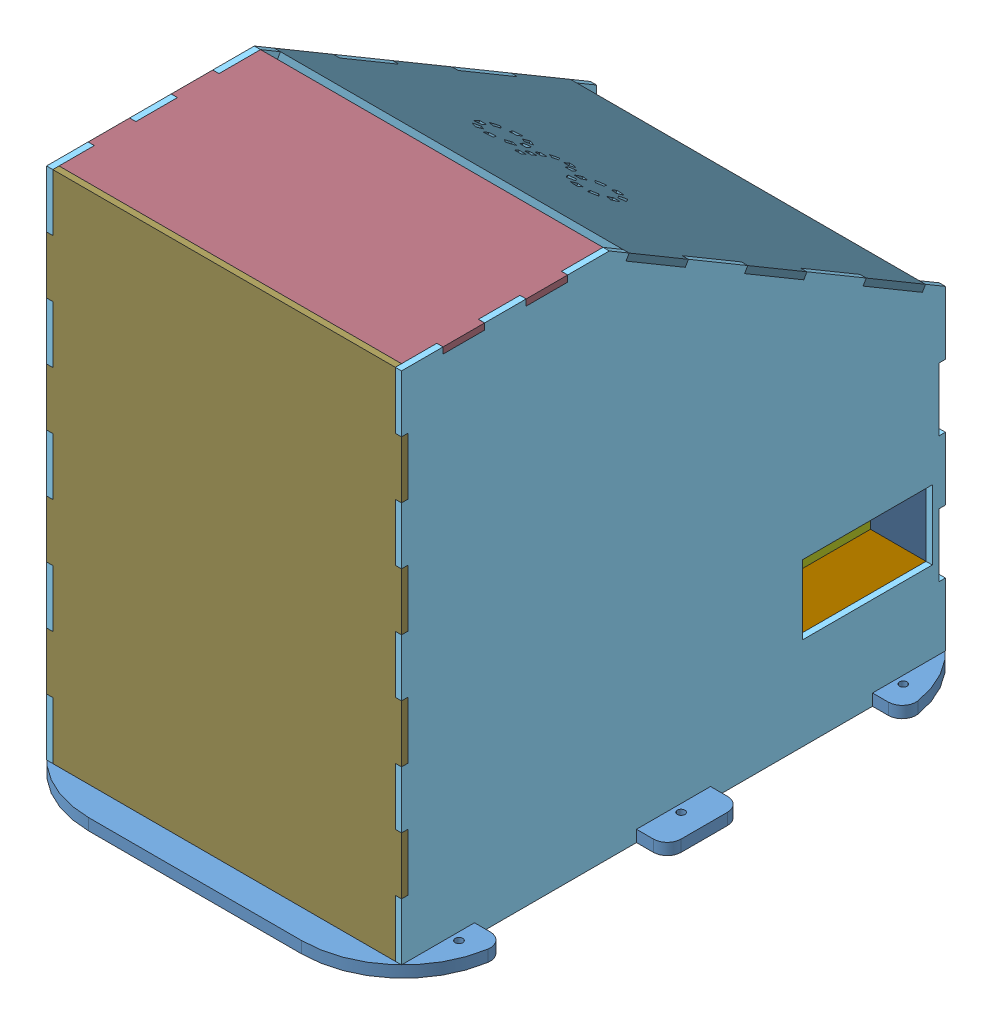
SolidWorks assembly Assem1_2, configuration Varsayılan. Lengths in mm.
Overall size (180 227.3 260).
24 component instances, 14 part files, 26 mates.
Components (placement in the parent):
- mainboard_last-1: mainboard_last [Varsayılan] at (-3.7025 2.4058 260) size (180 5 260)
- Assem-2: Assem [Varsayılan] at (36.9297 -4.2274 65.841) size (80 56 25)
  - holder_A_1-1: holder_A_1 [Varsayılan] at (-40.6321 11.6331 76.659) size (80 3 25)
  - holder_B_2-1: holder_B_2 [Varsayılan] at (-40.6321 20.6331 64.159) x (1 0 0) z (0 -1 0) size (80 3 56)
  - holder_D_1-1: holder_D_1 [Varsayılan] at (-40.6321 52.6331 68.659) size (80 3 9)
- Side_2-10: Side_2 [Varsayılan] at (72.9975 117.2058 260) x (-1 0 0) z (0 0 -1) size (2.7 227.3 235.04)
- Assem for solar panel holder-4: Assem for solar panel holder [Varsayılan] at (45.3941 8.6486 146.17) size (35.5 68 62)
  - part_A1-1: part_A1 [Varsayılan] at (-0.5965 -1.2429 30) size (20 3 30)
  - part_B1-3: part_B1 [Varsayılan] at (-2.0965 32.7571 30) size (3 68 62)
  - Part_E1-1: Part_E1 [Varsayılan] at (11.4035 63.7571 30) x (0 0 -1) z (1 0 0) size (62 3 27)
  - Part_F1-1: Part_F1 [Varsayılan] at (11.4035 30.7571 30) x (0 0 -1) z (1 0 0) size (62 3 27)
  - Part_C1-1: Part_C1 [Varsayılan] at (12.9035 48.7571 2) x (0 0 -1) z (-1 0 0) size (3 36 24)
  - Part_D1-1: Part_D1 [Varsayılan] at (12.9035 48.7571 61) x (0 0 -1) z (1 0 0) size (3 36 24)
- Side_2-11: Side_2 [Varsayılan] at (-77.7025 117.2058 260.0067) x (-1 0 0) z (0 0 -1) size (2.7 227.3 235.04)
- Assem for solar panel holder-5: Assem for solar panel holder [Varsayılan] at (-52.799 8.6486 206.17) x (-1 0 0) z (0 0 -1) size (35.5 68 62)
  - part_A1-1: part_A1 [Varsayılan] at (-0.5965 -1.2429 30) size (20 3 30)
  - part_B1-3: part_B1 [Varsayılan] at (-2.0965 32.7571 30) size (3 68 62)
  - Part_E1-1: Part_E1 [Varsayılan] at (11.4035 63.7571 30) x (0 0 -1) z (1 0 0) size (62 3 27)
  - Part_F1-1: Part_F1 [Varsayılan] at (11.4035 30.7571 30) x (0 0 -1) z (1 0 0) size (62 3 27)
  - Part_C1-1: Part_C1 [Varsayılan] at (12.9035 48.7571 2) x (0 0 -1) z (-1 0 0) size (3 36 24)
  - Part_D1-1: Part_D1 [Varsayılan] at (12.9035 48.7571 61) x (0 0 -1) z (1 0 0) size (3 36 24)
- Back-1: Back [Varsayılan] at (-3.7025 116.0558 374.8267) size (153.4 227.3 2.7)
- Top_first-3: Top_first [Varsayılan] at (-3.7025 227.0058 332.6417) size (153.4 2.7 87.07)
- Top_second-2: Top_second [Varsayılan] at (-3.7025 184.4308 216.4945) x (-1 0 0) z (0 -0.508987 -0.860774) size (153.4 2.7 148.77)
Mates (geometry in assembly coordinates):
- Coincident4: coincident aligned: circle of mainboard_last-1; circle of Assem-2/holder_A_1-1
- Coincident20: coincident aligned: plane of mainboard_last-1 through (-87.7025 2.4058 270) normal (0 -1 0); plane of Side_2-10 through (70.2975 2.4058 260) normal (0 -1 0)
- Coincident21: coincident anti-aligned: plane of mainboard_last-1 through (72.9975 7.4058 254.6667) normal (-1 0 0); plane of Side_2-10 through (72.9975 117.2058 260) normal (1 0 0)
- Coincident22: coincident anti-aligned: plane of mainboard_last-1 through (70.2975 7.4058 254.6667) normal (0 0 1); plane of Side_2-10 through (70.2975 117.2058 254.6667) normal (0 0 -1)
- Coincident25: coincident aligned: circle of mainboard_last-1; circle of Assem for solar panel holder-4/part_A1-1
- Coincident26: coincident anti-aligned: plane of mainboard_last-1 through (-77.7025 7.4058 174) normal (-1 0 0); plane of Side_2-11 through (-77.7025 117.2058 260.0067) normal (1 0 0)
- Coincident27: coincident anti-aligned: plane of mainboard_last-1 through (-77.7025 7.4058 367.02) normal (0 0 -1); plane of Side_2-11 through (-80.4025 117.2058 367.02) normal (0 0 1)
- Coincident29: coincident: plane of mainboard_last-1 through (-87.7025 2.4058 270) normal (0 -1 0); line of Side_2-11 through (-77.7025 2.4058 276.0067) axis (0 0 1)
- Coincident30: coincident aligned: circle of mainboard_last-1; circle of Assem for solar panel holder-5/part_A1-1
- Coincident31: coincident aligned: plane of Side_2-11 through (-80.4025 117.2058 377.5267) normal (0 0 1); plane of Back-1 through (-3.7025 116.0558 377.5267) normal (0 0 1)
- Coincident32: coincident aligned: plane of Side_2-11 through (-80.4025 229.7058 260.0067) normal (0 1 0); plane of Back-1 through (70.2975 229.7058 377.5267) normal (0 1 0)
- Coincident33: coincident aligned: plane of Side_2-10 through (72.9975 117.2058 260) normal (1 0 0); plane of Back-1 through (72.9975 180.3058 377.5267) normal (1 0 0)
- Coincident50: coincident aligned: plane of Side_2-11 through (-80.4025 117.2058 260.0067) normal (-1 0 0); plane of Top_first-3 through (-80.4025 229.7058 359.5727) normal (-1 0 0)
- Coincident51: coincident aligned: plane of Side_2-11 through (-80.4025 229.7058 260.0067) normal (0 1 0); plane of Top_first-3 through (-3.7025 229.7058 332.6417) normal (0 1 0)
- Coincident52: coincident anti-aligned: plane of Back-1 through (-3.7025 116.0558 374.8267) normal (0 0 -1); plane of Top_first-3 through (-77.7025 229.7058 374.8267) normal (0 0 1)
- Coincident53: coincident anti-aligned: plane of Side_2-11 through (-80.4025 153.4189 321.2486) normal (0 -0.508987 -0.860774); plane of Top_second-2 through (-80.4025 224.6159 279.1489) normal (0 0.508987 0.860774)
- Coincident54: coincident aligned: plane of Side_2-11 through (-80.4025 117.2058 260.0067) normal (-1 0 0); plane of Top_second-2 through (-80.4025 148.8939 151.0915) normal (-1 0 0)
- Coincident55: coincident: line of Side_2-11 through (-77.7025 179.1837 202.3162) axis (0 -0.508987 -0.860774); plane of Top_second-2 through (-3.7025 186.7549 215.1202) normal (0 0.860774 -0.508987)
- Coincident56: coincident aligned: circle of mainboard_last-1; circle of ?
- Coincident57: coincident aligned: circle of mainboard_last-1; circle of ?
- Coincident58: coincident aligned: circle of mainboard_last-1; circle of ?
- Coincident60: coincident aligned: circle of mainboard_last-1; circle of ?
- Concentric8: concentric aligned: circle of ?; circle of ?
- Coincident72: coincident: circle of ?; point of ?
- Coincident73: coincident: circle of ?; point of ?
- Coincident74: coincident: circle of ?; point of ?
